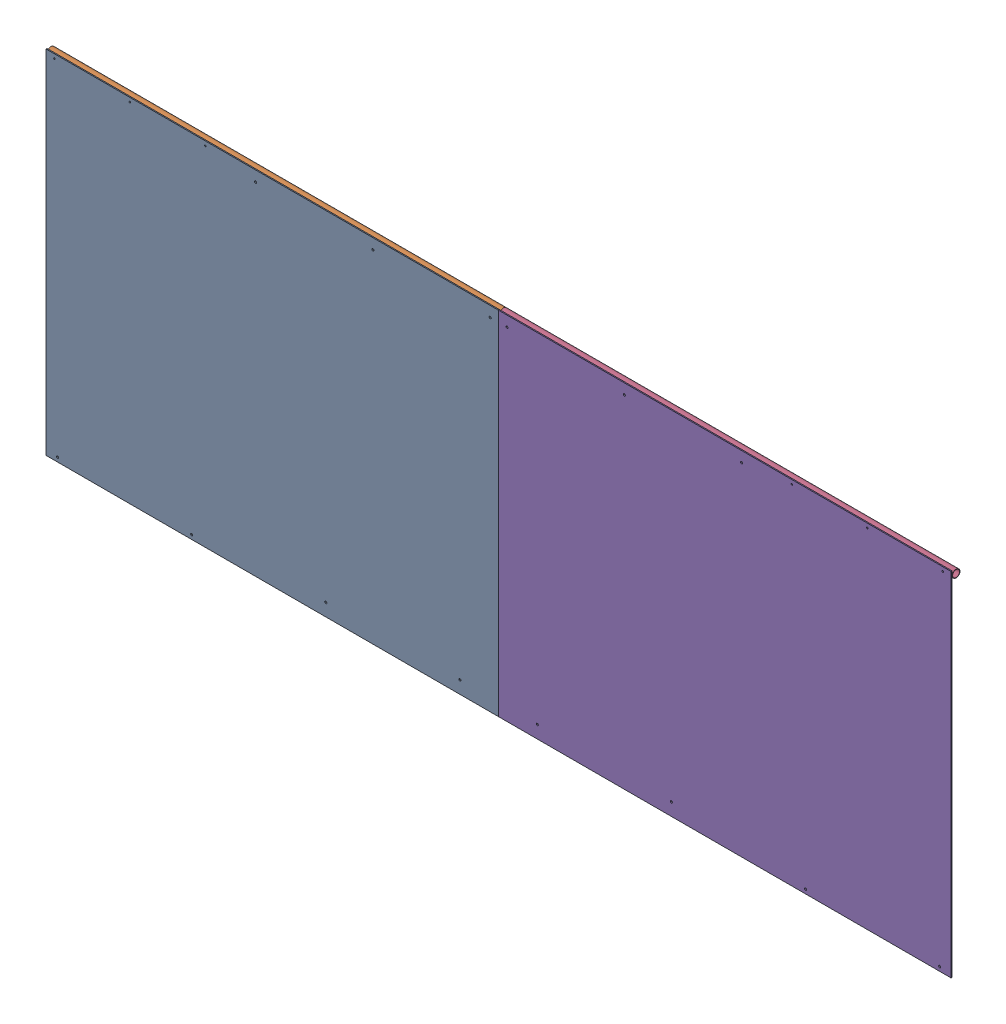
SolidWorks assembly GE-16107_ASM, configuration Default. Lengths in mm.
Overall size (2743.2 1066.8 26.59).
5 component instances, 4 part files, 0 mates.
Components (placement in the parent):
- GE-16108-1: GE-16108 [Default] at origin size (1371.6 1066.8 3.17)
- GE-16109-1: GE-16109 [Default] at (685.8 520.7 -14.8844) x (-1 0 0) z (0 0 1) size (1371.6 23.42 23.42)
- GE-16111-1: GE-16111 [Default] at (584.2 520.7 -14.8844) size (203.2 19.05 19.05)
- GE-16110-1: GE-16110 [Default] at (685.8 520.7 -14.8844) size (1371.6 23.42 23.42)
- GE-16108-2: GE-16108 [Default] at (1371.6 0 -3.175) x (-1 0 0) z (0 0 -1) size (1371.6 1066.8 3.17)
